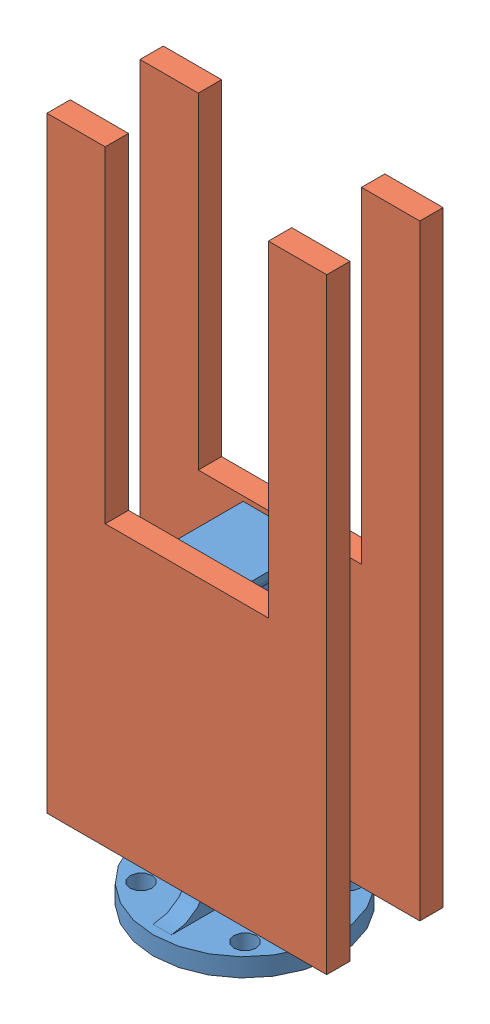
SolidWorks assembly xx--fake-hand-asm, configuration Default. Lengths in mm.
Overall size (76.2 175.18 50).
3 component instances, 2 part files, 6 mates.
Components (placement in the parent):
- wrist-1: wrist [Default] at origin size (50 85 50)
- xx-fake-hand-1: xx-fake-hand [Default] at (0 1.28 15.85) x (1 0 0) z (0 0 -1) size (76.2 165.1 6.35)
- xx-fake-hand-2: xx-fake-hand [Default] at (0 1.28 -9.5) x (1 0 0) z (0 0 -1) size (76.2 165.1 6.35)
Mates (geometry in assembly coordinates):
- Coincident1: coincident aligned: plane of xx-fake-hand-1 through (-22.225 90.18 9.5) normal (1 0 0); plane of xx-fake-hand-2 through (-22.225 90.18 -15.85) normal (1 0 0)
- Coincident2: coincident aligned: plane of xx-fake-hand-1 through (-22.225 1.28 9.5) normal (0 1 0); plane of xx-fake-hand-2 through (-22.225 1.28 -15.85) normal (0 1 0)
- Distance1: distance = 5.08 mm anti-aligned: plane of wrist-1 through (0 -80 0) normal (0 1 0); plane of xx-fake-hand-1 through (38.1 -74.92 9.5) normal (0 -1 0)
- Coincident4: coincident anti-aligned: plane of wrist-1 through (10 -80.001 -9.5) normal (0 0 -1); plane of xx-fake-hand-2 through (-22.225 -74.92 -9.5) normal (0 0 1)
- Coincident5: coincident anti-aligned: plane of wrist-1 through (10 -80.001 9.5) normal (0 0 1); plane of xx-fake-hand-1 through (-22.225 -74.92 9.5) normal (0 0 -1)
- Coincident6: coincident aligned: plane of wrist-1 through (0 0 0) normal (1 0 0); plane of xx-fake-hand-1 through (0 1.28 15.85) normal (1 0 0)
